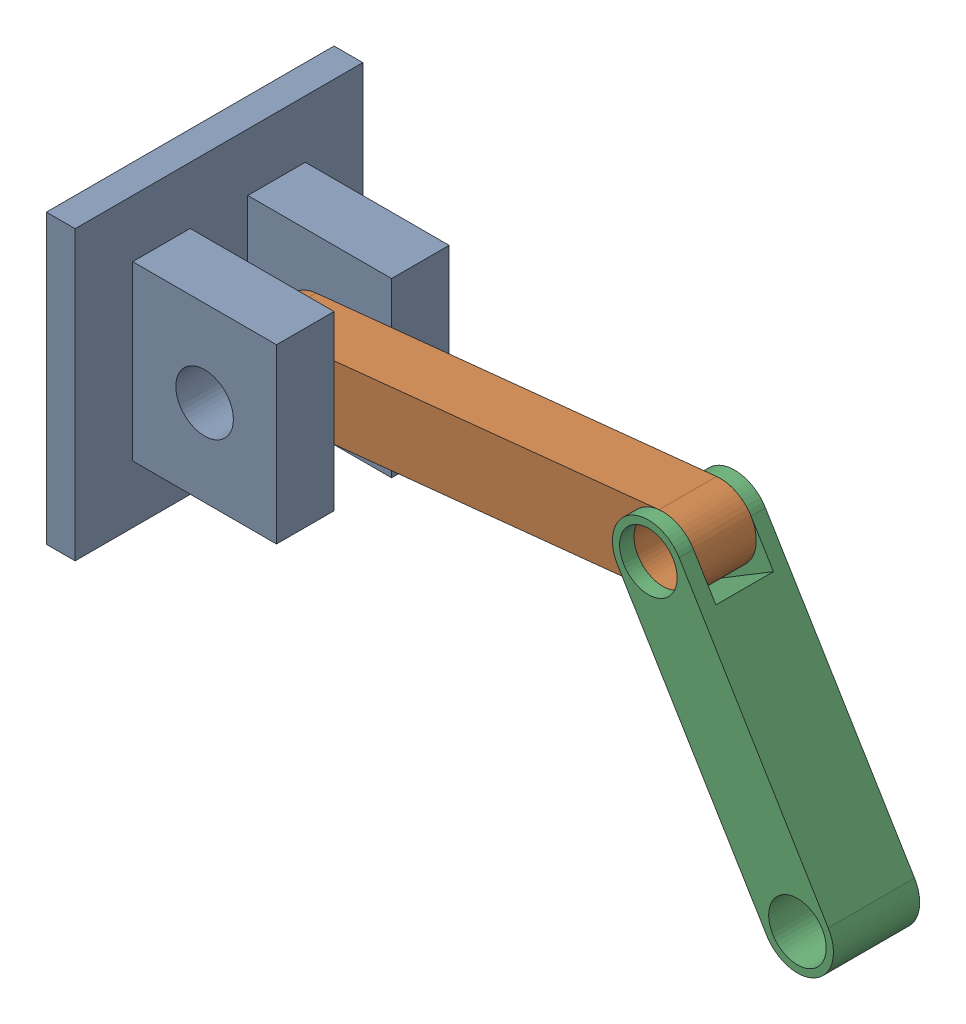
SolidWorks assembly Assem1, configuration Default. Lengths in mm.
Overall size (243.24 138.23 100).
3 component instances, 3 part files, 4 mates.
Components (placement in the parent):
- Fixado-1: Fixado [Default] at (-43.0307 42.2065 93.8321) size (60 100 100)
- Bracofixo-1: Bracofixo [Default] at (-8.0307 42.2825 93.8321) x (0.994699 0.102833 0) z (0 0 1) size (165 25 20)
- Bracoguincho-2: Bracoguincho [Default] at (131.2271 56.6792 93.8321) x (0.518127 -0.855304 0) z (0 0 -1) size (125 25 30)
Mates (geometry in assembly coordinates):
- Concentric2: concentric anti-aligned: cylinder of Fixado-1 through (-8.0307 42.2825 63.8321) axis (0 0 1) radius 10; cylinder of Bracofixo-1 through (-8.0307 42.2825 103.8321) axis (0 0 -1) radius 10
- Coincident2: coincident anti-aligned: plane of Fixado-1 through (16.9693 12.2825 103.8321) normal (0 0 -1); plane of Bracofixo-1 through (-8.0307 42.2825 103.8321) normal (0 0 1)
- Concentric3: concentric anti-aligned: cylinder of Bracofixo-1 through (131.2271 56.6792 103.8321) axis (0 0 -1) radius 10; cylinder of Bracoguincho-2 through (131.2271 56.6792 78.8321) axis (0 0 1) radius 10
- Coincident4: coincident anti-aligned: plane of Bracofixo-1 through (-8.0307 42.2825 103.8321) normal (0 0 1); plane of Bracoguincho-2 through (134.1465 75.9853 103.8321) normal (0 0 -1)
